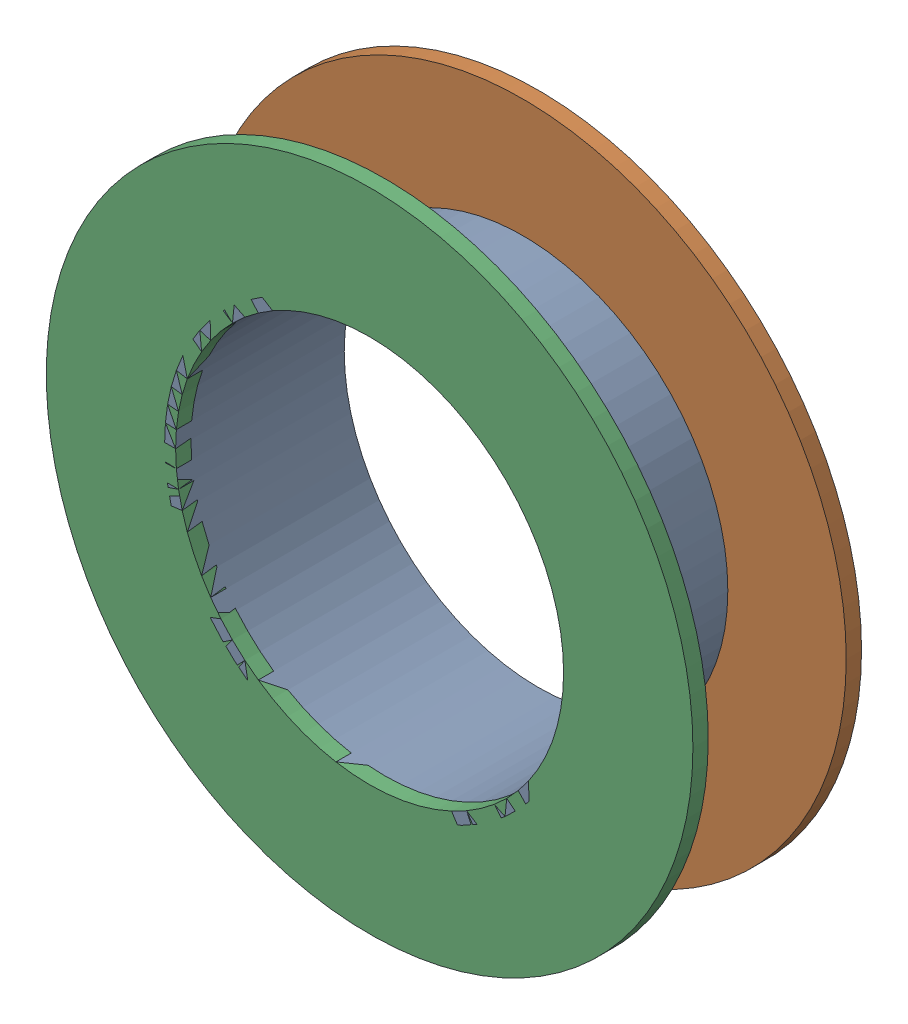
SolidWorks assembly Pad SWD-3(18.034mm,48.387mm) on Multi-Layer, configuration Predeterminado. Lengths in mm.
Overall size (1.5 1.5 0.39).
6 component instances, 2 part files, 0 mates.
Components (placement in the parent):
- Pad Hole-1-1: Pad Hole-1 [Predeterminado] at (18.034 48.387 -0.4013) size (0.95 0.95 0.39)
  - Pad Hole-Part-1-1-1: Pad Hole-Part-1-1 [Predeterminado] at origin size (0.95 0.95 0.39)
- Top Layer-1-1: Top Layer-1 [Predeterminado] at (18.034 48.387 -0.4013) size (1.5 1.5 0.04)
  - Top Layer-Part-1-1-1: Top Layer-Part-1-1 [Predeterminado] at origin size (1.5 1.5 0.04)
- Top Layer-1-2: Top Layer-1 [Predeterminado] at (18.034 48.387 -0.0457) size (1.5 1.5 0.04)
  - Top Layer-Part-1-1-1: Top Layer-Part-1-1 [Predeterminado] at origin size (1.5 1.5 0.04)
